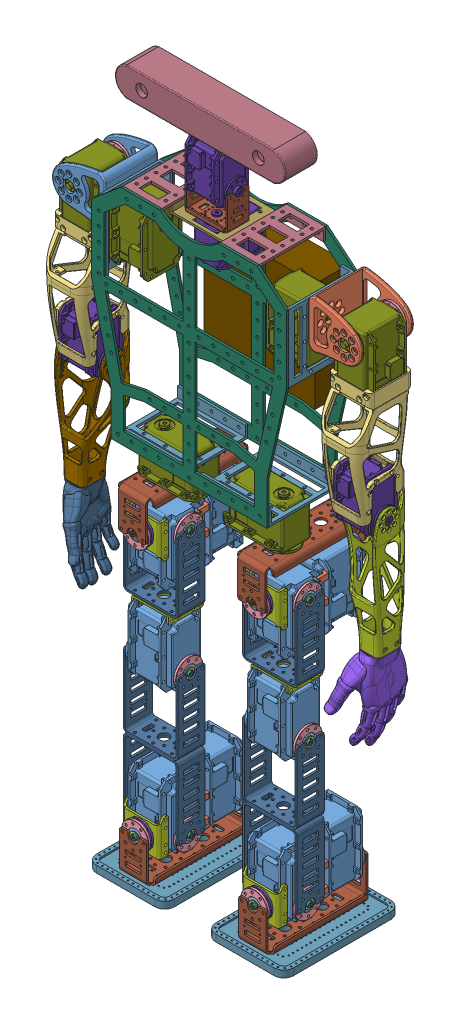
SolidWorks assembly main_new_feet, configuration Default. Lengths in mm.
Overall size (334.21 729.22 145.63).
144 component instances, 32 part files, 59 mates.
Components (placement in the parent):
- leg_l2-1: leg_l2 [Default] at (32.287 -223.4121 -197.7719) x (0 0 1) z (-1 0 0) size (106.88 70.06 58.88)
  - MX-106T_step-1: MX-106T_step [Default] at origin size (40.2 65.92 55.3)
  - MX-106T_step-2: MX-106T_step [Default] at (-44 0 0) x (0 0 1) z (-1 0 0) size (40.2 65.92 55.3)
  - FR08-X101_2017-1: FR08-X101_2017 [Default] at (-27 -7 -17) x (0 -1 0) z (0 0 1) size (28 12.3 4.8)
  - FR08-X101_2017-2: FR08-X101_2017 [Default] at (-27 -7 17) x (0 1 0) z (0 0 -1) size (28 12.3 4.8)
  - RX64-CAP_2017-1: RX64-CAP_2017 [Default] at (0 0 -25.78) x (0.56381 0.825904 0) z (0 0 -1) size (9.5 9.5 2.2)
  - HN05-I101_2017-1: HN05-I101_2017 [Default] at (0 0 -26.02) x (0.824833 -0.565376 0) z (0.565376 0.824833 0) size (28 3.77 28)
  - MF128ZZ_2017-1: MF128ZZ_2017 [Default] at (0 0 -22.3) x (-0.923728 -0.383049 0) z (0.383049 -0.923728 0) size (14 3.48 14)
  - WB_M2.5X8_2017-1: WB_M2.5X8_2017 [Default] at (0 0 -28.08) x (0 0 1) z (0.825904 -0.56381 0) size (5.5 4.5 4.5)
  - FR05-S101_2017-1: FR05-S101_2017 [Default] at (24 0 0) x (0 1 0) z (0 0 1) size (36 9.31 38.02)
  - FR05-F101_2017-1: FR05-F101_2017 [Default] at (24 0 0) x (0 -0.707107 0.707107) z (1 0 0) size (27 27 5)
  - MF128ZZ_2017-2: MF128ZZ_2017 [Default] at (26.3 0 0) x (0 -1 0) z (0 0 1) size (14 3.48 14)
  - WB_M2.5X8_step-1: WB_M2.5X8_step [Default] at (32.08 0 0) x (-1 0 0) z (0 0.546944 0.837169) size (10.5 4.5 4.5)
  - HN05-I101_2017-2: HN05-I101_2017 [Default] at (30.02 0 0) x (0 -1 0) z (0 0 1) size (28 3.77 28)
  - RX64-CAP_2017-2: RX64-CAP_2017 [Default] at (29.78 0 0) x (0 0.837169 -0.546944) z (1 0 0) size (9.5 9.5 2.2)
- leg_l3-2: leg_l3 [Default] at (9.4719 -309.3189 -145.539) x (1 0 0) z (0 1 0) size (58.88 41.6 149.21)
  - HW-64106HXL_2017-1: HW-64106HXL_2017 [Default] at (-3.1848 38.233 13.9067) size (56 28 75)
  - FR05-S101_2017-1: FR05-S101_2017 [Default] at (22.8152 52.233 13.9067) x (0 -1 0) z (1 0 0) size (36 9.31 38.02)
  - MX-106T_step-1: MX-106T_step [Default] at (22.8152 52.233 -40.5933) x (0 1 0) z (-1 0 0) size (40.2 65.92 55.3)
  - HN05-I101_2017-1: HN05-I101_2017 [Default] at (48.8352 52.233 -40.5933) x (0 -0.637924 -0.7701) z (0 -0.7701 0.637924) size (28 3.77 28)
  - RX64-CAP_2017-1: RX64-CAP_2017 [Default] at (48.5952 52.233 -40.5933) x (0 0.837169 -0.546944) z (1 0 0) size (9.5 9.5 2.2)
  - MF128ZZ_2017-1: MF128ZZ_2017 [Default] at (45.1152 52.233 -40.5933) x (0 -0.162836 -0.986653) z (0 -0.986653 0.162836) size (14 3.48 14)
  - WB_M2.5X8_2017-1: WB_M2.5X8_2017 [Default] at (50.8952 52.233 -40.5933) x (-1 0 0) z (0 0.546944 0.837169) size (5.5 4.5 4.5)
- leg_l4-1: leg_l4 [Default] at (-9.8792 -490.5806 -151.7825) x (1 0 0) z (0 1 0) size (56 28 150)
  - HW-64106HXL_2017-1: HW-64106HXL_2017 [Default] at (16.1663 31.9894 68.6685) size (56 28 75)
  - HW-64106HXL_2017-2: HW-64106HXL_2017 [Default] at (68.1663 31.9894 68.6685) x (-1 0 0) z (0 0 -1) size (56 28 75)
- leg_l5-1: leg_l5 [Default] at (76.8682 -440.5941 -231.6442) x (0.699193 -0.033567 0.714144) z (-0.673395 -0.366444 0.642073) size (104.02 99.97 119.36)
  - MX-106T_step-1: MX-106T_step [Default] at (-5.1915 -29.4269 71.3073) x (-0.714144 -0.278818 -0.642073) z (-0.699193 0.240141 0.673395) size (40.2 65.92 55.3)
  - MX-106T_step-2: MX-106T_step [Default] at (-36.6138 -41.6949 43.056) x (0.699193 -0.240141 -0.673395) z (-0.714144 -0.278818 -0.642073) size (40.2 65.92 55.3)
  - FR08-X101_2017-1: FR08-X101_2017 [Default] at (-36.5946 -26.3638 62.8539) x (-0.033567 0.929835 -0.366444) z (0.699193 -0.240141 -0.673395) size (28 12.3 4.8)
  - FR08-X101_2017-2: FR08-X101_2017 [Default] at (-12.8221 -34.5286 39.9585) x (0.033567 -0.929835 0.366444) z (-0.699193 0.240141 0.673395) size (28 12.3 4.8)
  - HN05-I101_2017-1: HN05-I101_2017 [Default] at (13.0015 -35.6754 53.7855) x (0.048348 -0.923861 0.379661) z (0.713296 0.298014 0.634347) size (28 3.77 28)
  - RX64-CAP_2017-1: RX64-CAP_2017 [Default] at (12.8337 -35.6178 53.9472) x (-0.430608 0.610431 -0.664793) z (0.699193 -0.240141 -0.673395) size (9.5 9.5 2.2)
  - HN05-I101_2017-2: HN05-I101_2017 [Default] at (16.2471 -21.0568 90.5823) x (0.601193 -0.714144 -0.35856) z (-0.35856 -0.642073 0.677626) size (28 3.77 28)
  - RX64-CAP_2017-2: RX64-CAP_2017 [Default] at (16.0757 -21.1237 90.4282) x (-0.307188 0.949038 -0.070448) z (0.714144 0.278818 0.642073) size (9.5 9.5 2.2)
  - MF128ZZ_2017-1: MF128ZZ_2017 [Default] at (10.4005 -34.7821 56.2906) x (0.048348 -0.923861 0.379661) z (0.713296 0.298014 0.634347) size (14 3.48 14)
  - WB_M2.5X8_2017-1: WB_M2.5X8_2017 [Default] at (14.4419 -36.1701 52.3983) x (-0.699193 0.240141 0.673395) z (0.570706 0.754788 0.323403) size (5.5 4.5 4.5)
  - MF128ZZ_2017-2: MF128ZZ_2017 [Default] at (13.5905 -22.094 88.1938) x (0.601193 -0.714144 -0.35856) z (-0.35856 -0.642073 0.677626) size (14 3.48 14)
  - WB_M2.5X8_2017-2: WB_M2.5X8_2017 [Default] at (17.7183 -20.4824 91.905) x (-0.714144 -0.278818 -0.642073) z (-0.628994 -0.146927 0.763399) size (5.5 4.5 4.5)
  - FR05-S101_2017-1: FR05-S101_2017 [Default] at (11.948 -22.7353 86.717) x (0.033567 -0.929835 0.366444) z (0.699193 -0.240141 -0.673395) size (36 9.31 38.02)
  - FR05-F101_2017-1: FR05-F101_2017 [Default] at (11.948 -22.7353 86.717) x (0.699193 -0.240141 -0.673395) z (0.714144 0.278818 0.642073) size (27 27 5)
- HW-64106HXW_2017-3: HW-64106HXW_2017 [Default] at (170.787 -186.4121 -265.7719) x (0 0 1) z (0 -1 0) size (105 37.08 40)
- leg_l2-2: leg_l2 [Default] at (154.787 -223.4121 -197.7719) x (0 0 1) z (-1 0 0) size (106.88 70.06 58.88)
  - MX-106T_step-1: MX-106T_step [Default] at origin size (40.2 65.92 55.3)
  - MX-106T_step-2: MX-106T_step [Default] at (-44 0 0) x (0 0 1) z (-1 0 0) size (40.2 65.92 55.3)
  - FR08-X101_2017-1: FR08-X101_2017 [Default] at (-27 -7 -17) x (0 -1 0) z (0 0 1) size (28 12.3 4.8)
  - FR08-X101_2017-2: FR08-X101_2017 [Default] at (-27 -7 17) x (0 1 0) z (0 0 -1) size (28 12.3 4.8)
  - RX64-CAP_2017-1: RX64-CAP_2017 [Default] at (0 0 -25.78) x (0.56381 0.825904 0) z (0 0 -1) size (9.5 9.5 2.2)
  - HN05-I101_2017-1: HN05-I101_2017 [Default] at (0 0 -26.02) x (0.824833 -0.565376 0) z (0.565376 0.824833 0) size (28 3.77 28)
  - MF128ZZ_2017-1: MF128ZZ_2017 [Default] at (0 0 -22.3) x (-0.923728 -0.383049 0) z (0.383049 -0.923728 0) size (14 3.48 14)
  - WB_M2.5X8_2017-1: WB_M2.5X8_2017 [Default] at (0 0 -28.08) x (0 0 1) z (0.825904 -0.56381 0) size (5.5 4.5 4.5)
  - FR05-S101_2017-1: FR05-S101_2017 [Default] at (24 0 0) x (0 1 0) z (0 0 1) size (36 9.31 38.02)
  - FR05-F101_2017-1: FR05-F101_2017 [Default] at (24 0 0) x (0 -0.707107 0.707107) z (1 0 0) size (27 27 5)
  - MF128ZZ_2017-2: MF128ZZ_2017 [Default] at (26.3 0 0) x (0 -1 0) z (0 0 1) size (14 3.48 14)
  - WB_M2.5X8_step-1: WB_M2.5X8_step [Default] at (32.08 0 0) x (-1 0 0) z (0 0.546944 0.837169) size (10.5 4.5 4.5)
  - HN05-I101_2017-2: HN05-I101_2017 [Default] at (30.02 0 0) x (0 -1 0) z (0 0 1) size (28 3.77 28)
  - RX64-CAP_2017-2: RX64-CAP_2017 [Default] at (29.78 0 0) x (0 0.837169 -0.546944) z (1 0 0) size (9.5 9.5 2.2)
- leg_l3-3: leg_l3 [Default] at (131.9719 -309.3189 -145.539) x (1 0 0) z (0 1 0) size (58.88 41.6 149.21)
  - HW-64106HXL_2017-1: HW-64106HXL_2017 [Default] at (-3.1848 38.233 13.9067) size (56 28 75)
  - FR05-S101_2017-1: FR05-S101_2017 [Default] at (22.8152 52.233 13.9067) x (0 -1 0) z (1 0 0) size (36 9.31 38.02)
  - MX-106T_step-1: MX-106T_step [Default] at (22.8152 52.233 -40.5933) x (0 1 0) z (-1 0 0) size (40.2 65.92 55.3)
  - HN05-I101_2017-1: HN05-I101_2017 [Default] at (48.8352 52.233 -40.5933) x (0 -0.637924 -0.7701) z (0 -0.7701 0.637924) size (28 3.77 28)
  - RX64-CAP_2017-1: RX64-CAP_2017 [Default] at (48.5952 52.233 -40.5933) x (0 0.837169 -0.546944) z (1 0 0) size (9.5 9.5 2.2)
  - MF128ZZ_2017-1: MF128ZZ_2017 [Default] at (45.1152 52.233 -40.5933) x (0 -0.162836 -0.986653) z (0 -0.986653 0.162836) size (14 3.48 14)
  - WB_M2.5X8_2017-1: WB_M2.5X8_2017 [Default] at (50.8952 52.233 -40.5933) x (-1 0 0) z (0 0.546944 0.837169) size (5.5 4.5 4.5)
- leg_l4-2: leg_l4 [Default] at (112.6208 -490.5806 -151.7825) x (1 0 0) z (0 1 0) size (56 28 150)
  - HW-64106HXL_2017-1: HW-64106HXL_2017 [Default] at (16.1663 31.9894 68.6685) size (56 28 75)
  - HW-64106HXL_2017-2: HW-64106HXL_2017 [Default] at (68.1663 31.9894 68.6685) x (-1 0 0) z (0 0 -1) size (56 28 75)
- leg_l5-2: leg_l5 [Default] at (199.3682 -440.5941 -231.6442) x (0.699193 -0.033567 0.714144) z (-0.673395 -0.366444 0.642073) size (104.02 99.97 119.36)
  - MX-106T_step-1: MX-106T_step [Default] at (-5.1915 -29.4269 71.3073) x (-0.714144 -0.278818 -0.642073) z (-0.699193 0.240141 0.673395) size (40.2 65.92 55.3)
  - MX-106T_step-2: MX-106T_step [Default] at (-36.6138 -41.6949 43.056) x (0.699193 -0.240141 -0.673395) z (-0.714144 -0.278818 -0.642073) size (40.2 65.92 55.3)
  - FR08-X101_2017-1: FR08-X101_2017 [Default] at (-36.5946 -26.3638 62.8539) x (-0.033567 0.929835 -0.366444) z (0.699193 -0.240141 -0.673395) size (28 12.3 4.8)
  - FR08-X101_2017-2: FR08-X101_2017 [Default] at (-12.8221 -34.5286 39.9585) x (0.033567 -0.929835 0.366444) z (-0.699193 0.240141 0.673395) size (28 12.3 4.8)
  - HN05-I101_2017-1: HN05-I101_2017 [Default] at (13.0015 -35.6754 53.7855) x (0.048348 -0.923861 0.379661) z (0.713296 0.298014 0.634347) size (28 3.77 28)
  - RX64-CAP_2017-1: RX64-CAP_2017 [Default] at (12.8337 -35.6178 53.9472) x (-0.430608 0.610431 -0.664793) z (0.699193 -0.240141 -0.673395) size (9.5 9.5 2.2)
  - HN05-I101_2017-2: HN05-I101_2017 [Default] at (16.2471 -21.0568 90.5823) x (0.601193 -0.714144 -0.35856) z (-0.35856 -0.642073 0.677626) size (28 3.77 28)
  - RX64-CAP_2017-2: RX64-CAP_2017 [Default] at (16.0757 -21.1237 90.4282) x (-0.307188 0.949038 -0.070448) z (0.714144 0.278818 0.642073) size (9.5 9.5 2.2)
  - MF128ZZ_2017-1: MF128ZZ_2017 [Default] at (10.4005 -34.7821 56.2906) x (0.048348 -0.923861 0.379661) z (0.713296 0.298014 0.634347) size (14 3.48 14)
  - WB_M2.5X8_2017-1: WB_M2.5X8_2017 [Default] at (14.4419 -36.1701 52.3983) x (-0.699193 0.240141 0.673395) z (0.570706 0.754788 0.323403) size (5.5 4.5 4.5)
  - MF128ZZ_2017-2: MF128ZZ_2017 [Default] at (13.5905 -22.094 88.1938) x (0.601193 -0.714144 -0.35856) z (-0.35856 -0.642073 0.677626) size (14 3.48 14)
  - WB_M2.5X8_2017-2: WB_M2.5X8_2017 [Default] at (17.7183 -20.4824 91.905) x (-0.714144 -0.278818 -0.642073) z (-0.628994 -0.146927 0.763399) size (5.5 4.5 4.5)
  - FR05-S101_2017-1: FR05-S101_2017 [Default] at (11.948 -22.7353 86.717) x (0.033567 -0.929835 0.366444) z (0.699193 -0.240141 -0.673395) size (36 9.31 38.02)
  - FR05-F101_2017-1: FR05-F101_2017 [Default] at (11.948 -22.7353 86.717) x (0.699193 -0.240141 -0.673395) z (0.714144 0.278818 0.642073) size (27 27 5)
- HW-64106HXW_2017-5: HW-64106HXW_2017 [Default] at (48.287 -186.4121 -265.7719) x (0 0 1) z (0 -1 0) size (105 37.08 40)
- torso-1: torso [Default] at (93.537 76.1289 -198.2719) size (217.43 273.5 112.95)
  - torso_frame_head-1: torso_frame_head [Default] at (0 -3.827 -35) size (76 8 58.5)
  - torso_frame_link-1: torso_frame_link [Default] at (-50 -6.241 0) x (0 0 1) z (-1 0 0) size (75.11 12.7 53.47)
  - torso_frame_motor-1: torso_frame_motor [Default] at (-98.857 -88.541 0) x (0 0 1) z (-1 0 0) size (68 70 36.25)
  - torso_main-1: torso_main [Default] at (0 0 34) size (200 228.5 2.29)
  - torso_main-2: torso_main [Default] at (0 0 -36.286) size (200 228.5 2.29)
  - torso_frame_link-2: torso_frame_link [Default] at (50 -6.241 0) x (0 0 1) z (-1 0 0) size (75.11 12.7 53.47)
  - torso_frame_motor-2: torso_frame_motor [Default] at (98.857 -88.541 0) x (0 0 -1) z (1 0 0) size (68 70 36.25)
  - torso_frame_motor-3: torso_frame_motor [Default] at (10 -220.898 0) x (0 0 -1) z (0 -1 0) size (68 70 36.25)
  - torso_frame_motor-4: torso_frame_motor [Default] at (-10 -220.898 0) x (0 0 1) z (0 -1 0) size (68 70 36.25)
  - MX-64T_step-1: MX-64T_step [Default] at (80.714 -37.291 0) x (0 0 -1) z (1 0 0) size (40.2 62.1 50)
  - MX-64T_step-2: MX-64T_step [Default] at (-80.714 -37.291 0) x (0 0 1) z (-1 0 0) size (40.2 62.1 50)
  - MX-64T_step-3: MX-64T_step [Default] at (61.25 -239.041 0) x (0 0 -1) z (0 -1 0) size (40.2 62.1 50)
  - MX-64T_step-4: MX-64T_step [Default] at (-61.25 -239.041 0) x (0 0 1) z (0 -1 0) size (40.2 62.1 50)
  - MX28_step-1: MX28_step [Default] at (11.9078 -61.4181 -29.7938) x (-1 0 0) z (0 1 0) size (35.6 50.71 42.6)
  - nuc-1: nuc [Default] at (0 -108.0269 -54.066) size (114.3 111.76 35.56)
- arm_shoulder_right-1: arm_shoulder_right [MX-28_Right] at (-41.4573 39.516 -207.4216) size (56.51 54.5 59.55)
- arm_shoulder_left-1: arm_shoulder_left [MX-28_Right] at (228.5313 39.516 -207.4216) size (56.51 54.5 59.55)
- arm_l2-1: arm_l2 [Default] at (-59.4585 -11.9064 -257.1398) size (45.99 187.91 62.65)
  - MX-64T_step-1: MX-64T_step [Default] at (11.6566 50.7443 49.8736) size (40.2 62.1 50)
  - HN05-I101_2017-1: HN05-I101_2017 [Default] at (11.6566 50.7443 26.3536) x (-0.978167 -0.207821 0) z (0.207821 -0.978167 0) size (28 3.77 28)
  - MF128ZZ_2017-1: MF128ZZ_2017 [Default] at (11.6566 50.7443 30.0736) x (-0.981893 -0.189437 0) z (0.189437 -0.981893 0) size (14 3.48 14)
  - RX64-CAP_2017-1: RX64-CAP_2017 [Default] at (11.6566 50.7443 26.5936) x (-0.772804 -0.634645 0) z (0 0 -1) size (9.5 9.5 2.2)
  - WB_M2.5X8_2017-1: WB_M2.5X8_2017 [Default] at (11.6566 50.7443 24.2936) x (0 0 1) z (-0.923728 -0.383049 0) size (5.5 4.5 4.5)
  - arm_upperarm-1: arm_upperarm [Default] at (-19.8184 -15.6443 22.4331) size (44.79 120.44 61.97)
  - MX28_step-1: MX28_step [Default] at (-30.9345 -67.7118 42.6951) x (0 0 1) z (1 0 0) size (35.6 50.71 42.6)
  - MX28_HN07-i101-1: MX28_HN07-i101 [Default] at (-8.5434 -105.0057 54.6029) x (0 0.707328 0.706886) z (0 -0.706886 0.707328) size (22 3.05 22)
  - MF106ZZ-1: MF106ZZ [Défaut] at (-8.3934 -105.0057 54.6029) x (0 -0.837169 -0.546944) z (0 -0.546944 0.837169) size (11.2 3 11.2)
  - RX28-CAP-1: RX28-CAP [Défaut] at (-8.3934 -105.0057 54.6029) x (0 0.357314 -0.933984) z (-1 0 0) size (7.2 7.2 1.8)
- arm_l2-2: arm_l2 [Default] at (223.2193 -11.9064 -257.0362) size (45.99 187.91 62.65)
  - MX-64T_step-1: MX-64T_step [Default] at (11.6566 50.7443 49.8736) size (40.2 62.1 50)
  - HN05-I101_2017-1: HN05-I101_2017 [Default] at (11.6566 50.7443 26.3536) x (-0.978167 -0.207821 0) z (0.207821 -0.978167 0) size (28 3.77 28)
  - MF128ZZ_2017-1: MF128ZZ_2017 [Default] at (11.6566 50.7443 30.0736) x (-0.981893 -0.189437 0) z (0.189437 -0.981893 0) size (14 3.48 14)
  - RX64-CAP_2017-1: RX64-CAP_2017 [Default] at (11.6566 50.7443 26.5936) x (-0.772804 -0.634645 0) z (0 0 -1) size (9.5 9.5 2.2)
  - WB_M2.5X8_2017-1: WB_M2.5X8_2017 [Default] at (11.6566 50.7443 24.2936) x (0 0 1) z (-0.923728 -0.383049 0) size (5.5 4.5 4.5)
  - arm_upperarm-1: arm_upperarm [Default] at (-19.8184 -15.6443 22.4331) size (44.79 120.44 61.97)
  - MX28_step-1: MX28_step [Default] at (-30.9345 -67.7118 42.6951) x (0 0 1) z (1 0 0) size (35.6 50.71 42.6)
  - MX28_HN07-i101-1: MX28_HN07-i101 [Default] at (-8.5434 -105.0057 54.6029) x (0 0.707328 0.706886) z (0 -0.706886 0.707328) size (22 3.05 22)
  - MF106ZZ-1: MF106ZZ [Défaut] at (-8.3934 -105.0057 54.6029) x (0 -0.837169 -0.546944) z (0 -0.546944 0.837169) size (11.2 3 11.2)
  - RX28-CAP-1: RX28-CAP [Défaut] at (-8.3934 -105.0057 54.6029) x (0 0.357314 -0.933984) z (-1 0 0) size (7.2 7.2 1.8)
- arm_l3-1: arm_l3 [Default] at (204.6652 -273.2178 -305.5465) size (55.2 228.71 65.03)
  - arm_forearm_left-2: arm_forearm_left [MX-28-right] at (51.4657 156.3057 103.1131) size (55.2 137.66 53.14)
  - arm_hand_left-1: arm_hand_left [left_fake_human_like_hand] at (40.8108 36.3057 99.1131) x (0 0 -1) z (0 -1 0) size (64.5 37.73 100.68)
- arm_r3-1: arm_r3 [Default] at (-61.115 -260.9793 -320.9419) size (55.2 228.71 65.03)
  - arm_forearm_right-1: arm_forearm_right [MX-28-right] at (13.5631 144.0672 118.4049) size (55.2 137.66 53.14)
  - arm_hand_right-1: arm_hand_right [left_fake_human_like_hand] at (3.2131 24.0672 114.4049) x (0 0 -1) z (0 -1 0) size (59.65 36.84 100.68)
- FR07-H101K-1: FR07-H101K [Default] at (93.537 78.0519 -190.7719) x (-1 0 0) z (0 1 0) size (44 26 32.5)
- head_2-1: head_2 [Default] at (77.6258 211.8282 -253.1181) size (175 84.64 38.65)
  - MX28_step-1: MX28_step [Default] at (-26.9298 -63.9825 50.4384) x (0 0 1) z (1 0 0) size (35.6 50.71 42.6)
  - MX28_HN07-i101-1: MX28_HN07-i101 [Default] at (-4.5387 -101.2764 62.3462) x (0 0.153917 -0.988084) z (0 0.988084 0.153917) size (22 3.05 22)
  - MF106ZZ-1: MF106ZZ [Défaut] at (-4.3887 -101.2764 62.3462) x (0 0.577041 0.816715) z (0 0.816715 -0.577041) size (11.2 3 11.2)
  - RX28-CAP-1: RX28-CAP [Défaut] at (-4.3887 -101.2764 62.3462) x (0 1 0) z (-1 0 0) size (7.2 7.2 1.8)
  - FR07-S101K-1: FR07-S101K [Default] at (15.6613 -60.4964 62.0962) x (-1 0 0) z (0 1 0) size (33 27.5 8.5)
  - ZED-Body-1: ZED-Body [Default] at (15.6613 -44.1964 46.4962) size (175 30 38)
- leg_l6_new_feet-1: leg_l6_new_feet [Default] at (-17.1217 -592.3515 -262.8127) x (0 0 1) z (0 1 0) size (120 80 45.5)
  - HW-64106HXW_2017-1: HW-64106HXW_2017 [Default] at (-3.9692 33.4087 61.4394) size (105 37.08 40)
  - foot_new-1: foot_new [Default] at (44.5308 49.4087 55.9394) x (1 0 0) z (0 -1 0) size (120 7 80)
- leg_l6_new_feet-2: leg_l6_new_feet [Default] at (105.3783 -592.3515 -262.8127) x (0 0 1) z (0 1 0) size (120 80 45.5)
  - HW-64106HXW_2017-1: HW-64106HXW_2017 [Default] at (-3.9692 33.4087 61.4394) size (105 37.08 40)
  - foot_new-1: foot_new [Default] at (44.5308 49.4087 55.9394) x (1 0 0) z (0 -1 0) size (120 7 80)
Mates (geometry in assembly coordinates):
- Concentric3: concentric anti-aligned: cylinder of leg_l2-1/HN05-I101_2017-1 through (58.307 -223.4121 -197.7719) axis (-1 0 0) radius 14; cylinder of leg_l3-2/HW-64106HXL_2017-1 through (60.287 -223.4121 -197.7719) axis (1 0 0) radius 5.1
- Concentric4: concentric anti-aligned: cylinder of leg_l3-2/HN05-I101_2017-1 through (58.307 -349.9121 -197.7719) axis (-1 0 0) radius 14; cylinder of leg_l4-1/HW-64106HXL_2017-1 through (60.287 -349.9121 -197.7719) axis (1 0 0) radius 5.1
- Concentric5: concentric anti-aligned: cylinder of leg_l4-1/HW-64106HXL_2017-2 through (4.287 -493.9121 -197.7719) axis (-1 0 0) radius 5.1; cylinder of leg_l5-1/MX-106T_step-1 through (1.097 -493.9121 -197.7719) axis (1 0 0) radius 5
- Coincident5: coincident anti-aligned: plane of leg_l4-1/HW-64106HXL_2017-2 through (6.287 -493.9121 -197.7719) normal (1 0 0); plane of leg_l5-1/MX-106T_step-1 through (6.287 -493.9121 -197.7719) normal (-1 0 0)
- Coincident6: coincident anti-aligned: plane of leg_l2-1/MX-106T_step-1 through (6.287 -223.4121 -197.7719) normal (-1 0 0); plane of leg_l3-2/HW-64106HXL_2017-1 through (6.287 -223.4121 -197.7719) normal (1 0 0)
- Coincident7: coincident anti-aligned: plane of leg_l2-1/MX-106T_step-1 through (6.287 -223.4121 -197.7719) normal (-1 0 0); plane of leg_l3-2/HW-64106HXL_2017-1 through (6.287 -223.4121 -197.7719) normal (1 0 0)
- Coincident8: coincident anti-aligned: plane of leg_l3-2/MX-106T_step-1 through (6.287 -349.9121 -197.7719) normal (-1 0 0); plane of leg_l4-1/HW-64106HXL_2017-1 through (6.287 -349.9121 -197.7719) normal (1 0 0)
- Concentric8: concentric aligned: cylinder of HW-64106HXW_2017-3 through (154.787 -223.4121 -164.7719) axis (0 0 1) radius 5.1; cylinder of leg_l2-2/MX-106T_step-2 through (154.787 -223.4121 -272.9619) axis (0 0 1) radius 5
- Coincident11: coincident anti-aligned: plane of HW-64106HXW_2017-3 through (154.787 -208.4961 -267.7719) normal (0 0 1); plane of leg_l2-2/MX-106T_step-2 through (154.787 -223.4121 -267.7719) normal (0 0 -1)
- Concentric9: concentric aligned: cylinder of leg_l2-2/MX-106T_step-1 through (123.597 -223.4121 -197.7719) axis (1 0 0) radius 5; cylinder of leg_l3-3/HW-64106HXL_2017-1 through (128.787 -223.4121 -197.7719) axis (1 0 0) radius 5.1
- Coincident12: coincident anti-aligned: plane of leg_l2-2/MX-106T_step-1 through (128.787 -223.4121 -197.7719) normal (-1 0 0); plane of leg_l3-3/HW-64106HXL_2017-1 through (128.787 -223.4121 -197.7719) normal (1 0 0)
- Concentric10: concentric aligned: cylinder of leg_l3-3/MX-106T_step-1 through (123.597 -349.9121 -197.7719) axis (1 0 0) radius 5; cylinder of leg_l4-2/HW-64106HXL_2017-1 through (128.787 -349.9121 -197.7719) axis (1 0 0) radius 5.1
- Coincident13: coincident anti-aligned: plane of leg_l3-3/MX-106T_step-1 through (128.787 -349.9121 -197.7719) normal (-1 0 0); plane of leg_l4-2/HW-64106HXL_2017-1 through (128.787 -349.9121 -197.7719) normal (1 0 0)
- Concentric13: concentric anti-aligned: cylinder of leg_l4-2/HW-64106HXL_2017-2 through (126.787 -493.9121 -197.7719) axis (-1 0 0) radius 5.1; cylinder of leg_l5-2/MX-106T_step-1 through (123.597 -493.9121 -197.7719) axis (1 0 0) radius 5
- Coincident16: coincident anti-aligned: plane of leg_l4-2/HW-64106HXL_2017-2 through (128.787 -493.9121 -197.7719) normal (1 0 0); plane of leg_l5-2/MX-106T_step-1 through (128.787 -493.9121 -197.7719) normal (-1 0 0)
- Parallel3: parallel anti-aligned: plane of leg_l2-1/MX-106T_step-1 through (32.287 -223.4121 -197.7719) normal (0 0 1); plane of leg_l3-2/HW-64106HXL_2017-1 through (6.287 -295.4121 -183.7719) normal (0 0 -1)
- Parallel4: parallel aligned: plane of leg_l3-2/MX-106T_step-1 through (32.287 -349.9121 -197.7719) normal (0 0 -1); plane of leg_l4-1/HW-64106HXL_2017-1 through (6.287 -421.9121 -183.7719) normal (0 0 -1)
- Parallel5: parallel aligned: plane of leg_l4-1/HW-64106HXL_2017-2 through (58.287 -421.9121 -183.7719) normal (0 0 -1); plane of leg_l5-1/MX-106T_step-1 through (32.287 -493.9121 -197.7719) normal (0 0 -1)
- Parallel8: parallel aligned: plane of HW-64106HXW_2017-3 through (170.787 -186.4121 -265.7719) normal (-1 0 0); plane of leg_l2-2/MX-106T_step-1 through (154.787 -223.4121 -197.7719) normal (-1 0 0)
- Parallel9: parallel anti-aligned: plane of leg_l2-2/MX-106T_step-1 through (154.787 -223.4121 -197.7719) normal (0 0 1); plane of leg_l3-3/HW-64106HXL_2017-1 through (128.787 -295.4121 -183.7719) normal (0 0 -1)
- Parallel10: parallel aligned: plane of leg_l3-3/MX-106T_step-1 through (154.787 -349.9121 -197.7719) normal (0 0 -1); plane of leg_l4-2/HW-64106HXL_2017-1 through (128.787 -421.9121 -183.7719) normal (0 0 -1)
- Parallel11: parallel aligned: plane of leg_l4-2/HW-64106HXL_2017-2 through (180.787 -421.9121 -183.7719) normal (0 0 -1); plane of leg_l5-2/MX-106T_step-1 through (154.787 -493.9121 -197.7719) normal (0 0 -1)
- Concentric19: concentric aligned: cylinder of leg_l2-1/MX-106T_step-2 through (32.287 -223.4121 -272.9619) axis (0 0 1) radius 5; cylinder of HW-64106HXW_2017-5 through (32.287 -223.4121 -164.7719) axis (0 0 1) radius 5.1
- Coincident39: coincident anti-aligned: plane of leg_l2-1/MX-106T_step-2 through (32.287 -223.4121 -267.7719) normal (0 0 -1); plane of HW-64106HXW_2017-5 through (32.287 -208.4961 -267.7719) normal (0 0 1)
- Parallel18: parallel aligned: plane of leg_l2-1/MX-106T_step-1 through (32.287 -223.4121 -197.7719) normal (-1 0 0); plane of HW-64106HXW_2017-5 through (48.287 -186.4121 -265.7719) normal (-1 0 0)
- Concentric21: concentric anti-aligned: cylinder of HW-64106HXW_2017-5 through (32.287 -304.7334 -198.2719) axis (0 -1 0) radius 5.1; cylinder of torso-1/MX-64T_step-4 through (32.287 -191.2871 -198.2719) axis (0 1 0) radius 5
- Coincident43: coincident anti-aligned: plane of HW-64106HXW_2017-5 through (32.287 -186.4121 -192.0219) normal (0 1 0); plane of torso-1/MX-64T_step-4 through (32.287 -186.4121 -198.2719) normal (0 -1 0)
- Concentric22: concentric anti-aligned: cylinder of HW-64106HXW_2017-3 through (154.787 -304.7334 -198.2719) axis (0 -1 0) radius 5.1; cylinder of torso-1/MX-64T_step-3 through (154.787 -191.2871 -198.2719) axis (0 1 0) radius 2.75
- Coincident44: coincident anti-aligned: plane of HW-64106HXW_2017-3 through (154.787 -186.4121 -192.0219) normal (0 1 0); plane of torso-1/MX-64T_step-3 through (154.787 -186.4121 -198.2719) normal (0 -1 0)
- Concentric23: concentric aligned: cylinder of torso-1/MX-64T_step-2 through (-15.552 38.8379 -198.2719) axis (1 0 0) radius 14; cylinder of arm_shoulder_right-1 through (-65.2657 38.8379 -198.2719) axis (1 0 0) radius 5.8437
- Coincident45: coincident anti-aligned: plane of torso-1/MX-64T_step-2 through (-10.677 38.8379 -198.2719) normal (-1 0 0); plane of arm_shoulder_right-1 through (-10.677 14.0879 -234.5375) normal (1 0 0)
- Concentric24: concentric aligned: cylinder of torso-1/MX-64T_step-1 through (202.626 38.8379 -198.2719) axis (-1 0 0) radius 5; cylinder of arm_shoulder_left-1 through (252.3398 38.8379 -198.2719) axis (-1 0 0) radius 5.8437
- Coincident46: coincident anti-aligned: plane of torso-1/MX-64T_step-1 through (197.751 38.8379 -198.2719) normal (1 0 0); plane of arm_shoulder_left-1 through (197.751 14.0879 -234.5375) normal (-1 0 0)
- Concentric25: concentric aligned: cylinder of arm_shoulder_right-1 through (-47.8019 38.8379 -234.5375) axis (0 0 1) radius 5.8437; cylinder of arm_l2-1/HN05-I101_2017-1 through (-47.8019 38.8379 -230.7862) axis (0 0 1) radius 14
- Coincident47: coincident anti-aligned: plane of arm_shoulder_right-1 through (-32.0359 19.8146 -230.7562) normal (0 0 1); plane of arm_l2-1/HN05-I101_2017-1 through (-76.3429 48.0664 -230.7562) normal (0 0 -1)
- Concentric26: concentric anti-aligned: cylinder of arm_shoulder_left-1 through (234.876 38.8379 -234.5375) axis (0 0 1) radius 5.8437; cylinder of arm_l2-2/MX-64T_step-1 through (234.876 38.8379 -178.7876) axis (0 0 -1) radius 14
- Coincident48: coincident anti-aligned: plane of arm_shoulder_left-1 through (219.11 19.8146 -183.6626) normal (0 0 -1); plane of arm_l2-2/MX-64T_step-1 through (234.876 38.8379 -183.6626) normal (0 0 1)
- Concentric27: concentric anti-aligned: cylinder of arm_l2-2/MX28_step-1 through (258.7685 -116.9121 -202.4333) axis (-1 0 0) radius 4; cylinder of arm_l3-1/arm_forearm_left-2 through (207.9968 -116.9121 -202.4333) axis (1 0 0) radius 4.1
- Coincident49: coincident anti-aligned: plane of arm_l2-2/MX28_step-1 through (255.626 -116.9121 -202.4333) normal (1 0 0); plane of arm_l3-1/arm_forearm_left-2 through (255.626 -116.9121 -202.4333) normal (-1 0 0)
- Concentric28: concentric anti-aligned: cylinder of arm_l2-1/MX28_HN07-i101-1 through (-68.1544 -116.9121 -202.537) axis (1 0 0) radius 11; cylinder of arm_r3-1/arm_forearm_right-1 through (-20.4227 -116.9121 -202.537) axis (-1 0 0) radius 4.1
- Coincident50: coincident anti-aligned: plane of arm_l2-1/MX28_step-1 through (-27.0519 -116.9121 -202.537) normal (1 0 0); plane of arm_r3-1/arm_forearm_right-1 through (-27.0519 -116.9121 -202.537) normal (-1 0 0)
- Concentric29: concentric aligned: cylinder of torso-1/MX28_step-1 through (93.537 81.1944 -190.7719) axis (0 -1 0) radius 4; cylinder of FR07-H101K-1 through (93.537 79.5519 -190.7719) axis (0 -1 0) radius 4
- Coincident52: coincident anti-aligned: plane of torso-1/MX28_step-1 through (93.537 78.0519 -190.7719) normal (0 1 0); plane of FR07-H101K-1 through (93.537 78.0519 -190.7719) normal (0 -1 0)
- Concentric30: concentric aligned: cylinder of FR07-H101K-1 through (115.537 110.5519 -190.7719) axis (-1 0 0) radius 4; cylinder of head_2-1/MX28_step-1 through (117.1795 110.5519 -190.7719) axis (-1 0 0) radius 11
- Coincident53: coincident anti-aligned: plane of FR07-H101K-1 through (114.037 110.5519 -190.7719) normal (-1 0 0); plane of head_2-1/MX28_step-1 through (114.037 110.5519 -190.7719) normal (1 0 0)
- Parallel20: parallel aligned: plane of arm_shoulder_right-1 through (-16.177 14.0879 -234.5375) normal (-1 0 0); plane of arm_l2-1/MX-64T_step-1 through (-62.3019 51.8379 -227.7662) normal (-1 0 0)
- Parallel21: parallel aligned: plane of torso-1/torso_main-1 through (93.537 116.1289 -161.9859) normal (0 0 1); plane of arm_shoulder_right-1 through (-32.0359 19.8146 -179.8813) normal (0 0 1)
- Parallel22: parallel aligned: plane of torso-1/torso_main-1 through (93.537 116.1289 -161.9859) normal (0 0 1); plane of arm_shoulder_left-1 through (219.11 19.8146 -179.8813) normal (0 0 1)
- Parallel23: parallel aligned: plane of arm_shoulder_left-1 through (203.251 14.0879 -234.5375) normal (1 0 0); plane of arm_l2-2/MX-64T_step-1 through (249.376 -3.6621 -227.6626) normal (1 0 0)
- Parallel24: parallel: plane of arm_l2-2/MX28_step-1 through (217.126 -83.9121 -190.2333) normal (0 0 1); line of arm_l3-1/arm_forearm_left-2 through (258.626 -132.4346 -213.2367) axis (0 1 0)
- Parallel25: parallel: plane of arm_l2-1/MX28_step-1 through (-65.5519 -128.9121 -214.737) normal (0 0 -1); line of arm_r3-1/arm_forearm_right-1 through (-70.8977 -113.5973 -214.2896) axis (0 -1 0)
- Parallel26: parallel aligned: plane of torso-1/torso_main-1 through (93.537 116.1289 -161.9859) normal (0 0 1); plane of FR07-H101K-1 through (73.037 78.0519 -179.7719) normal (0 0 1)
- Parallel27: parallel aligned: plane of FR07-H101K-1 through (73.037 78.0519 -179.7719) normal (0 0 1); plane of head_2-1/MX28_step-1 through (80.287 143.1519 -172.9719) normal (0 0 1)
- Concentric31: concentric: cylinder of leg_l5-1/HN05-I101_2017-2 through (32.287 -493.9121 -167.7519) axis (0 0 -1) radius 14; cylinder of leg_l6_new_feet-1/HW-64106HXW_2017-1 through (32.287 -493.9121 -165.7819) axis (0 0 1) radius 5.1
- Coincident54: coincident: plane of leg_l5-1/HN05-I101_2017-2 through (62.2222 -495.8207 -167.7819) normal (0 0 1); plane of leg_l6_new_feet-1/HW-64106HXW_2017-1 through (32.287 -508.8282 -167.7819) normal (0 0 -1)
- Concentric33: concentric: cylinder of leg_l5-2/HN05-I101_2017-2 through (154.787 -493.9121 -167.7519) axis (0 0 -1) radius 14; cylinder of leg_l6_new_feet-2/HW-64106HXW_2017-1 through (154.787 -493.9121 -165.7819) axis (0 0 1) radius 5.1
- Coincident55: coincident: plane of leg_l5-2/HN05-I101_2017-2 through (184.7222 -495.8207 -167.7819) normal (0 0 1); plane of leg_l6_new_feet-2/HW-64106HXW_2017-1 through (160.7555 -507.582 -167.7819) normal (0 0 -1)
- Parallel28: parallel aligned: plane of leg_l5-1/MX-106T_step-1 through (55.287 -508.4121 -212.2719) normal (0 -1 0); plane of leg_l6_new_feet-1/foot_new-1 through (32.287 -536.4121 -218.2819) normal (0 -1 0)
- Parallel29: parallel aligned: plane of leg_l5-2/MX-106T_step-1 through (177.787 -508.4121 -212.2719) normal (0 -1 0); plane of leg_l6_new_feet-2/foot_new-1 through (154.787 -536.4121 -218.2819) normal (0 -1 0)
